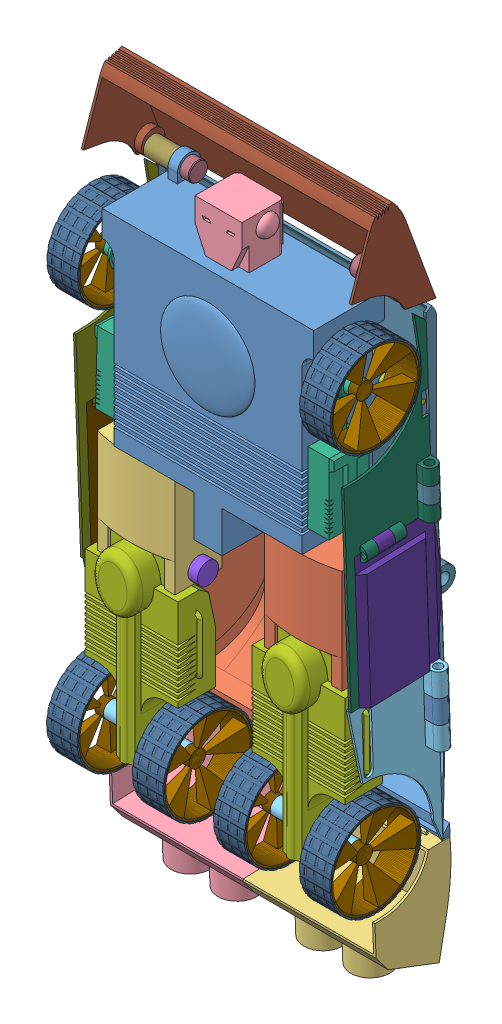
SolidWorks assembly TransformerX_StationaryMode, configuration Default. Lengths in mm.
Overall size (126 297.18 89.36).
45 component instances, 25 part files, 113 mates.
Components (placement in the parent):
- Body-1: Body [Default] at (46.3768 50.8704 65.1566) size (90 111.5 41.19)
- Leg2_left-1: Leg2_left [Default] at (81.8768 16.1704 65.1566) size (33 44.2 22.31)
- Leg2_right-1: Leg2_right [Default] at (10.8768 16.1704 65.1566) size (33 44.2 22.31)
- Head-1: Head [Default] at (46.3768 135.8704 65.1566) size (26 20 18.29)
- Axis-1: Axis [Default] at (81.8768 8.9704 65.1566) x (0 0 1) z (-1 0 0) size (7 7 39)
- Axis-2: Axis [Default] at (10.8768 8.9704 65.1566) x (0 -0.784262 0.62043) z (-1 0 0) size (7 7 39)
- Arm-4: Arm [Default] at (1.8768 74.3852 70.0913) x (-1 0 0) z (0 -0.027558 -0.99962) size (24 60 17)
- Arm-5: Arm [Default] at (90.8768 74.3707 69.1678) x (1 0 0) z (0 0.003878 0.999992) size (24 60 17)
- Leg1-1: Leg1 [Default] at (81.8768 -15.6296 69.1566) size (44.5 80.02 25)
- Leg1-2: Leg1 [Default] at (10.8768 -15.6296 69.1566) size (44.5 80.02 25)
- Axis-3: Axis [Default] at (10.8768 -57.5296 69.1566) x (0 -0.957762 -0.287561) z (-1 0 0) size (7 7 39)
- Axis-4: Axis [Default] at (81.8768 -57.5296 69.1566) x (0 -0.784262 0.62043) z (-1 0 0) size (7 7 39)
- Locker-1: Locker [Default] at (98.3768 8.9704 65.1566) x (0 0.219799 -0.975545) z (1 0 0) size (9 9 4)
- Locker-2: Locker [Default] at (-5.6232 8.9704 65.1566) x (0 0 1) z (-1 0 0) size (9 9 4)
- Locker-3: Locker [Default] at (27.3768 8.9704 65.1566) x (0 0.855004 -0.518621) z (1 0 0) size (9 9 4)
- Locker-4: Locker [Default] at (65.3768 8.9704 65.1566) x (0 -0.128282 -0.991738) z (-1 0 0) size (9 9 4)
- Wheel-1: Wheel [Default] at (-7.3732 -57.5296 69.1566) x (0 0.25642 0.966566) z (-1 0 0) size (37.5 37.5 12.5)
- Wheel-2: Wheel [Default] at (29.1268 -57.5296 69.1566) x (0 -0.360685 0.932688) z (1 0 0) size (37.5 37.5 12.5)
- Wheel-3: Wheel [Default] at (63.6268 -57.5296 69.1566) x (0 0.360685 -0.932688) z (-1 0 0) size (37.5 37.5 12.5)
- Wheel-4: Wheel [Default] at (100.1268 -57.5296 69.1566) x (0 -0.360685 0.932688) z (1 0 0) size (37.5 37.5 12.5)
- Wheel-5: Wheel [Default] at (100.1268 113.3704 69.0166) x (0 0.145658 0.989335) z (1 0 0) size (37.5 37.5 12.5)
- Wheel-6: Wheel [Default] at (-7.3732 113.3704 69.0166) x (0 -0.858748 -0.512398) z (-1 0 0) size (37.5 37.5 12.5)
- Tire-1: Tire [Default] at (63.6268 -57.5296 69.1566) x (0 0.693664 -0.720299) z (1 0 0) size (38.8 38.79 13)
- Tire-2: Tire [Default] at (-7.3732 -57.5296 69.1566) x (0 0.899399 0.437129) z (1 0 0) size (38.8 38.79 13)
- Tire-3: Tire [Default] at (29.1268 -57.5296 69.1566) x (0 -0.851002 0.525162) z (-1 0 0) size (38.8 38.79 13)
- Tire-4: Tire [Default] at (-7.3732 113.3704 69.0166) x (0 -0.247928 -0.968779) z (1 0 0) size (38.8 38.79 13)
- Tire-5: Tire [Default] at (100.1268 -57.5296 69.1566) x (0 -0.693664 0.720299) z (-1 0 0) size (38.8 38.79 13)
- Tire-6: Tire [Default] at (100.1268 113.3704 69.0166) x (0 0.041073 0.999156) z (-1 0 0) size (38.8 38.79 13)
- CarPart1-1: CarPart1 [Default] at (46.3768 146.4917 57.8937) x (0 0.985256 -0.171089) z (-1 0 0) size (40.79 38 115)
- Axis3-1: Axis3 [Default] at (92.1268 139.8704 50.1566) x (0 0 -1) z (1 0 0) size (8 8 19.5)
- Axis3-2: Axis3 [Default] at (0.6268 139.8704 50.1566) x (0 0.924225 0.381849) z (-1 0 0) size (8 8 19.5)
- Locker2-2: Locker2 [Default] at (10.3768 139.8704 50.1566) x (0 0.082275 0.99661) z (-1 0 0) size (8 8 4)
- Locker2-3: Locker2 [Default] at (82.3768 139.8704 50.1566) x (0 -0.889675 -0.456595) z (1 0 0) size (8 8 4)
- CarPart2-1: CarPart2 [Default] at (46.3768 67.0428 42.5993) x (0 0.999342 0.03628) z (-1 0 0) size (131.64 36.94 126)
- CarPart3_left-1: CarPart3_left [Default] at (103.3768 56.1884 72.8454) x (0 0.999342 0.03628) z (-1 0 0) size (132.4 36.62 6.5)
- CarPart3_right-1: CarPart3_right [Default] at (-10.6232 56.1884 72.8454) x (0 0.999342 0.03628) z (-1 0 0) size (132.4 36.62 6.5)
- CarPart_Door_left-1: CarPart_Door_left [Default] at (103.8768 28.4816 57.37) x (0 0.999342 0.03628) z (-1 0 0) size (59.5 53.92 22.75)
- CarPart_Door_right-1: CarPart_Door_right [Default] at (-10.1232 28.4816 57.37) x (0 0.999342 0.03628) z (-1 0 0) size (59.5 53.92 22.75)
- CarPart4_left-1: CarPart4_left [Default] at (74.6268 -33.3547 37.9538) x (0 0.999342 0.03628) z (-1 0 0) size (78.5 35.5 63)
- CarPart4_right-1: CarPart4_right [Default] at (18.1268 -33.3547 37.9538) x (0 0.999342 0.03628) z (-1 0 0) size (78.5 35.5 63)
- CarPart5_left-1: CarPart5_left [Default] at (74.6268 -82.0545 35.6855) x (0 -0.999342 -0.03628) z (1 0 0) size (48.5 32.62 56.5)
- CarPart5_right-1: CarPart5_right [Default] at (18.1268 -82.0545 35.6855) x (0 -0.999342 -0.03628) z (1 0 0) size (48.5 32.62 56.5)
- CarPart6_left-1: CarPart6_left [Default] at (102.8768 -34.287 56.7424) x (0 0.999342 0.03628) z (-1 0 0) size (69 37.62 7.5)
- CarPart6_right-1: CarPart6_right [Default] at (-9.1232 -34.287 56.7424) x (0 0.999342 0.03628) z (-1 0 0) size (69 37.62 7.5)
- Axis4-1: Axis4 [Default] at (46.3768 97.8704 45.1566) x (0 0 1) z (-1 0 0) size (5.5 5.5 113)
Mates (geometry in assembly coordinates):
- Concentric1: concentric aligned: cylinder of Body-1 through (74.3768 40.6704 65.1566) axis (-1 0 0) radius 3.5; cylinder of Leg2_left-1 through (74.3768 40.6704 65.1566) axis (-1 0 0) radius 3.5
- Coincident1: coincident anti-aligned: plane of Body-1 through (74.3768 40.6704 65.1566) normal (1 0 0); plane of Leg2_left-1 through (74.3768 40.6704 65.1566) normal (-1 0 0)
- Concentric2: concentric aligned: cylinder of Body-1 through (18.3768 40.6704 65.1566) axis (1 0 0) radius 3.5; cylinder of Leg2_right-1 through (18.3768 40.6704 65.1566) axis (1 0 0) radius 3.5
- Coincident2: coincident anti-aligned: plane of Body-1 through (18.3768 40.6704 65.1566) normal (-1 0 0); plane of Leg2_right-1 through (18.3768 40.6704 65.1566) normal (1 0 0)
- Parallel1: parallel aligned: plane of Leg2_left-1 through (65.3768 48.1704 55.1566) normal (0 0 -1); plane of Leg2_right-1 through (-5.6232 48.1704 55.1566) normal (0 0 -1)
- Parallel2: parallel aligned: plane of Body-1 through (91.3768 135.8704 50.1566) normal (0 0 -1); plane of Leg2_right-1 through (-5.6232 48.1704 55.1566) normal (0 0 -1)
- Concentric3: concentric aligned: cylinder of Body-1 through (46.3768 142.8704 65.1566) axis (0 -1 0) radius 4.5; cylinder of Head-1 through (46.3768 142.8704 65.1566) axis (0 -1 0) radius 4.5
- Coincident5: coincident anti-aligned: plane of Body-1 through (46.3768 142.8704 65.1566) normal (0 1 0); plane of Head-1 through (46.3768 142.8704 65.1566) normal (0 -1 0)
- Parallel3: parallel aligned: plane of Body-1 through (1.3768 135.8704 80.1566) normal (0 0 1); plane of Head-1 through (46.3768 135.8704 75.6566) normal (0 0 1)
- Concentric4: concentric anti-aligned: cylinder of Leg2_right-1 through (27.3768 8.9704 65.1566) axis (-1 0 0) radius 3.5; cylinder of Axis-2 through (32.2535 8.9704 65.1566) axis (1 0 0) radius 3.5
- Coincident7: coincident aligned: plane of Leg2_right-1 through (27.3768 48.1704 55.1566) normal (1 0 0); plane of Axis-2 through (27.3768 7.0097 66.7076) normal (1 0 0)
- Concentric5: concentric anti-aligned: cylinder of Leg2_left-1 through (98.3768 8.9704 65.1566) axis (-1 0 0) radius 3.5; cylinder of Axis-1 through (103.2535 8.9704 65.1566) axis (1 0 0) radius 3.5
- Coincident8: coincident aligned: plane of Leg2_left-1 through (98.3768 48.1704 55.1566) normal (1 0 0); plane of Axis-1 through (98.3768 8.9704 67.6566) normal (1 0 0)
- Concentric6: concentric aligned: cylinder of Body-1 through (77.3768 113.3704 69.0166) axis (1 0 0) radius 3.5; cylinder of Arm-5 through (77.3768 113.3704 69.0166) axis (1 0 0) radius 3.5
- Coincident9: coincident anti-aligned: plane of Body-1 through (86.3768 50.8704 50.1555) normal (1 0 0); plane of Arm-5 through (86.3768 74.3707 69.1678) normal (-1 0 0)
- Concentric7: concentric aligned: cylinder of Body-1 through (15.3768 113.3704 69.0166) axis (-1 0 0) radius 3.5; cylinder of Arm-4 through (15.3768 113.3704 69.0166) axis (-1 0 0) radius 3.5
- Coincident10: coincident anti-aligned: plane of Body-1 through (6.3768 50.8704 50.1555) normal (-1 0 0); plane of Arm-4 through (6.3768 74.3852 70.0913) normal (1 0 0)
- Concentric8: concentric aligned: cylinder of Axis-1 through (103.2535 8.9704 65.1566) axis (1 0 0) radius 3.5; cylinder of Leg1-1 through (62.1258 8.9704 65.1566) axis (1 0 0) radius 3.75
- Coincident11: coincident anti-aligned: plane of Leg2_left-1 through (93.8768 16.1704 65.1566) normal (-1 0 0); plane of Leg1-1 through (93.8768 8.9704 65.1566) normal (1 0 0)
- Concentric9: concentric anti-aligned: cylinder of Axis-2 through (32.2535 8.9704 65.1566) axis (1 0 0) radius 3.5; cylinder of Leg1-2 through (30.6278 8.9704 65.1566) axis (-1 0 0) radius 3.75
- Coincident12: coincident anti-aligned: plane of Leg2_right-1 through (22.8768 16.1704 65.1566) normal (-1 0 0); plane of Leg1-2 through (22.8768 8.9704 65.1566) normal (1 0 0)
- Parallel4: parallel aligned: plane of Leg1-1 through (67.8768 -45.2296 61.1566) normal (0 0 -1); plane of Leg1-2 through (-3.1232 -45.2296 61.1566) normal (0 0 -1)
- Parallel5: parallel aligned: plane of Leg2_left-1 through (65.3768 48.1704 55.1566) normal (0 0 -1); plane of Leg1-1 through (67.8768 -45.2296 61.1566) normal (0 0 -1)
- Concentric10: concentric anti-aligned: cylinder of Leg1-2 through (30.6278 -57.5296 69.1566) axis (-1 0 0) radius 3.5; cylinder of Axis-3 through (32.2535 -57.5296 69.1566) axis (1 0 0) radius 3.5
- Width2: width aligned: plane of Leg1-2 through (14.8768 -63.0296 77.1566) normal (1 0 0); plane of Leg1-2 through (6.8768 -63.0296 77.1566) normal (-1 0 0); plane of Axis-3 through (27.3768 -59.924 68.4377) normal (1 0 0); plane of Axis-3 through (-5.6232 -60.8818 68.1501) normal (-1 0 0)
- Concentric11: concentric anti-aligned: cylinder of Leg1-1 through (101.6278 -57.5296 69.1566) axis (-1 0 0) radius 3.5; cylinder of Axis-4 through (103.2535 -57.5296 69.1566) axis (1 0 0) radius 3.5
- Width3: width aligned: plane of Leg1-1 through (77.8768 -63.0296 77.1566) normal (-1 0 0); plane of Leg1-1 through (85.8768 -63.0296 77.1566) normal (1 0 0); plane of Axis-4 through (65.3768 -60.2746 71.3281) normal (-1 0 0); plane of Axis-4 through (98.3768 -59.4903 70.7076) normal (1 0 0)
- Concentric12: concentric aligned: cylinder of Axis-2 through (32.2535 8.9704 65.1566) axis (1 0 0) radius 2.5; cylinder of Locker-2 through (-9.6232 8.9704 65.1566) axis (1 0 0) radius 4.5
- Coincident15: coincident anti-aligned: plane of Leg2_right-1 through (-5.6232 48.1704 55.1566) normal (-1 0 0); plane of Locker-2 through (-5.6232 8.9704 65.1566) normal (1 0 0)
- Concentric13: concentric anti-aligned: cylinder of Axis-1 through (103.2535 8.9704 65.1566) axis (1 0 0) radius 2.5; cylinder of Locker-1 through (102.3768 8.9704 65.1566) axis (-1 0 0) radius 4.5
- Coincident16: coincident anti-aligned: plane of Leg2_left-1 through (98.3768 48.1704 55.1566) normal (1 0 0); plane of Locker-1 through (98.3768 8.9704 65.1566) normal (-1 0 0)
- Concentric14: concentric anti-aligned: cylinder of Axis-2 through (32.2535 8.9704 65.1566) axis (1 0 0) radius 2.5; cylinder of Locker-3 through (31.3768 8.9704 65.1566) axis (-1 0 0) radius 4.5
- Coincident17: coincident anti-aligned: plane of Leg2_right-1 through (27.3768 48.1704 55.1566) normal (1 0 0); plane of Locker-3 through (27.3768 8.9704 65.1566) normal (-1 0 0)
- Concentric15: concentric aligned: cylinder of Axis-1 through (103.2535 8.9704 65.1566) axis (1 0 0) radius 2.5; cylinder of Locker-4 through (62.3768 8.9704 65.1566) axis (1 0 0) radius 2.5
- Coincident18: coincident anti-aligned: plane of Leg2_left-1 through (65.3768 48.1704 55.1566) normal (-1 0 0); plane of Locker-4 through (65.3768 8.9704 65.1566) normal (1 0 0)
- Concentric16: concentric aligned: cylinder of Axis-3 through (32.2535 -57.5296 69.1566) axis (1 0 0) radius 2.5; cylinder of Wheel-1 through (-8.6232 -57.5296 69.1566) axis (1 0 0) radius 2.5
- Coincident19: coincident anti-aligned: plane of Axis-3 through (-5.6232 -60.8818 68.1501) normal (-1 0 0); plane of Wheel-1 through (-5.6232 -58.4271 65.7736) normal (1 0 0)
- Concentric17: concentric anti-aligned: cylinder of Axis-3 through (32.2535 -57.5296 69.1566) axis (1 0 0) radius 2.5; cylinder of Wheel-2 through (30.3768 -57.5296 69.1566) axis (-1 0 0) radius 2.5
- Coincident20: coincident anti-aligned: plane of Axis-3 through (27.3768 -59.924 68.4377) normal (1 0 0); plane of Wheel-2 through (27.3768 -56.2672 65.8922) normal (-1 0 0)
- Concentric18: concentric aligned: cylinder of Axis-4 through (103.2535 -57.5296 69.1566) axis (1 0 0) radius 2.5; cylinder of Wheel-3 through (62.3768 -57.5296 69.1566) axis (1 0 0) radius 2.5
- Coincident21: coincident anti-aligned: plane of Axis-4 through (65.3768 -60.2746 71.3281) normal (-1 0 0); plane of Wheel-3 through (65.3768 -58.792 72.421) normal (1 0 0)
- Concentric19: concentric anti-aligned: cylinder of Axis-4 through (103.2535 -57.5296 69.1566) axis (1 0 0) radius 2.5; cylinder of Wheel-4 through (101.3768 -57.5296 69.1566) axis (-1 0 0) radius 2.5
- Coincident22: coincident anti-aligned: plane of Axis-4 through (98.3768 -59.4903 70.7076) normal (1 0 0); plane of Wheel-4 through (98.3768 -56.2672 65.8922) normal (-1 0 0)
- Concentric20: concentric aligned: cylinder of Arm-4 through (-8.6232 113.3704 69.0166) axis (1 0 0) radius 2.5; cylinder of Wheel-6 through (-8.6232 113.3704 69.0166) axis (1 0 0) radius 2.5
- Coincident23: coincident anti-aligned: plane of Arm-4 through (-5.6232 113.3704 69.0166) normal (-1 0 0); plane of Wheel-6 through (-5.6232 116.376 70.81) normal (1 0 0)
- Concentric21: concentric aligned: cylinder of Arm-5 through (101.3768 113.3704 69.0166) axis (-1 0 0) radius 2.5; cylinder of Wheel-5 through (101.3768 113.3704 69.0166) axis (-1 0 0) radius 2.5
- Coincident24: coincident anti-aligned: plane of Arm-5 through (98.3768 113.3704 69.0166) normal (1 0 0); plane of Wheel-5 through (98.3768 112.8606 65.5539) normal (-1 0 0)
- Parallel6: parallel aligned: plane of Wheel-3 through (63.6268 -57.1837 69.6967) normal (0 -0.539304 -0.842111); plane of Wheel-4 through (100.1268 -57.1837 69.6967) normal (0 -0.539304 -0.842111)
- Parallel7: parallel aligned: plane of Wheel-1 through (-7.3732 -57.1837 69.6967) normal (0 -0.539304 -0.842111); plane of Wheel-2 through (29.1268 -57.1837 69.6967) normal (0 -0.539304 -0.842111)
- Parallel8: parallel aligned: plane of Wheel-2 through (29.1268 -57.1837 69.6967) normal (0 -0.539304 -0.842111); plane of Wheel-3 through (63.6268 -57.1837 69.6967) normal (0 -0.539304 -0.842111)
- Concentric22: concentric anti-aligned: cylinder of Wheel-1 through (27.7862 -57.5296 69.1566) axis (1 0 0) radius 18.75; cylinder of Tire-2 through (-0.8722 -57.5296 69.1566) axis (-1 0 0) radius 18.75
- Width4: width aligned: plane of Wheel-1 through (-13.6232 -57.5296 69.1566) normal (-1 0 0); plane of Wheel-1 through (-1.1232 -62.3375 51.0335) normal (1 0 0); plane of Tire-2 through (-13.8732 -57.5296 69.1566) normal (-1 0 0); plane of Tire-2 through (-0.8732 -57.5296 69.1566) normal (1 0 0)
- Concentric23: concentric anti-aligned: cylinder of Wheel-2 through (-6.0326 -57.5296 69.1566) axis (-1 0 0) radius 18.75; cylinder of Tire-3 through (22.6258 -57.5296 69.1566) axis (1 0 0) radius 18.75
- Width5: width aligned: plane of Wheel-2 through (35.3768 -57.5296 69.1566) normal (1 0 0); plane of Wheel-2 through (22.8768 -50.7668 51.6687) normal (-1 0 0); plane of Tire-3 through (35.6268 -57.5296 69.1566) normal (1 0 0); plane of Tire-3 through (22.6268 -57.5296 69.1566) normal (-1 0 0)
- Concentric24: concentric anti-aligned: cylinder of Wheel-3 through (98.7862 -57.5296 69.1566) axis (1 0 0) radius 18.75; cylinder of Tire-1 through (70.1278 -57.5296 69.1566) axis (-1 0 0) radius 18.75
- Width6: width aligned: plane of Wheel-3 through (69.8768 -64.2925 86.6445) normal (1 0 0); plane of Wheel-3 through (57.3768 -57.5296 69.1566) normal (-1 0 0); plane of Tire-1 through (70.1268 -57.5296 69.1566) normal (1 0 0); plane of Tire-1 through (57.1268 -57.5296 69.1566) normal (-1 0 0)
- Concentric25: concentric anti-aligned: cylinder of Wheel-4 through (64.9674 -57.5296 69.1566) axis (-1 0 0) radius 18.75; cylinder of Tire-5 through (93.6258 -57.5296 69.1566) axis (1 0 0) radius 18.75
- Width7: width aligned: plane of Wheel-4 through (93.8768 -50.7668 51.6687) normal (-1 0 0); plane of Wheel-4 through (106.3768 -57.5296 69.1566) normal (1 0 0); plane of Tire-5 through (93.6268 -57.5296 69.1566) normal (-1 0 0); plane of Tire-5 through (106.6268 -57.5296 69.1566) normal (1 0 0)
- Concentric26: concentric anti-aligned: cylinder of Wheel-6 through (27.7862 113.3704 69.0166) axis (1 0 0) radius 18.75; cylinder of Tire-4 through (-0.8722 113.3704 69.0166) axis (-1 0 0) radius 18.75
- Concentric27: concentric anti-aligned: cylinder of Wheel-5 through (64.9674 113.3704 69.0166) axis (-1 0 0) radius 18.75; cylinder of Tire-6 through (93.6258 113.3704 69.0166) axis (1 0 0) radius 18.75
- Width8: width anti-aligned: plane of Wheel-5 through (106.3768 113.3704 69.0166) normal (1 0 0); plane of Wheel-5 through (93.8768 110.6393 50.4665) normal (-1 0 0); plane of Tire-6 through (93.6268 113.3704 69.0166) normal (-1 0 0); plane of Tire-6 through (106.6268 113.3704 69.0166) normal (1 0 0)
- Width9: width aligned: plane of Wheel-6 through (-13.6232 113.3704 69.0166) normal (-1 0 0); plane of Wheel-6 through (-1.1232 129.4719 78.624) normal (1 0 0); plane of Tire-4 through (-13.8732 113.3704 69.0166) normal (-1 0 0); plane of Tire-4 through (-0.8732 113.3704 69.0166) normal (1 0 0)
- Parallel9: parallel aligned: plane of Wheel-4 through (100.1268 -57.1796 69.694) normal (0 -0.545797 -0.837917); plane of Tire-5 through (100.1268 -57.5296 69.1566) normal (0 -0.545797 -0.837917)
- Parallel10: parallel aligned: plane of Wheel-3 through (63.6268 -57.1796 69.694) normal (0 -0.545797 -0.837917); plane of Tire-1 through (63.6268 -57.5296 69.1566) normal (0 -0.545797 -0.837917)
- Parallel11: parallel aligned: plane of Wheel-2 through (29.1268 -57.1796 69.694) normal (0 -0.545797 -0.837917); plane of Tire-3 through (29.1268 -57.5296 69.1566) normal (0 -0.545797 -0.837917)
- Parallel12: parallel aligned: plane of Wheel-1 through (-7.3732 -57.9326 69.6556) normal (0 0.628246 -0.778015); plane of Tire-2 through (-7.3732 -57.5296 69.1566) normal (0 0.628246 -0.778015)
- Parallel13: parallel aligned: plane of Wheel-5 through (100.1268 113.0877 68.4409) normal (0 0.440785 0.897613); plane of Tire-6 through (100.1268 113.3704 69.0166) normal (0 0.440785 0.897613)
- Parallel14: parallel anti-aligned: plane of Wheel-6 through (-7.3732 112.7455 68.8718) normal (0 0.974193 0.225718); plane of Tire-4 through (-7.3732 113.3704 69.0166) normal (0 -0.974193 -0.225718)
- Concentric28: concentric anti-aligned: cylinder of Body-1 through (1.3058 139.8704 50.1566) axis (1 0 0) radius 2.5; cylinder of CarPart1-1 through (101.8768 139.8704 50.1566) axis (-1 0 0) radius 2.5
- Width10: width anti-aligned: plane of Body-1 through (91.3768 135.8704 80.1566) normal (1 0 0); plane of Body-1 through (1.3768 135.8704 50.1566) normal (-1 0 0); plane of CarPart1-1 through (-11.1232 128.6596 72.1015) normal (-1 0 0); plane of CarPart1-1 through (103.8768 128.6596 72.1015) normal (1 0 0)
- Concentric30: concentric aligned: cylinder of CarPart1-1 through (101.8768 139.8704 50.1566) axis (-1 0 0) radius 2.5; cylinder of Axis3-1 through (63.5942 139.8704 50.1566) axis (-1 0 0) radius 2.5
- Coincident36: coincident anti-aligned: plane of Body-1 through (88.3768 139.8704 50.1566) normal (1 0 0); plane of Axis3-1 through (88.3768 139.8704 47.6566) normal (-1 0 0)
- Concentric31: concentric anti-aligned: cylinder of Body-1 through (15.4479 139.8704 50.1566) axis (-1 0 0) radius 2.5; cylinder of Axis3-2 through (29.1595 139.8704 50.1566) axis (1 0 0) radius 2.5
- Coincident37: coincident anti-aligned: plane of CarPart1-1 through (-7.1232 141.0527 49.9513) normal (1 0 0); plane of Axis3-2 through (-7.1232 143.5673 51.684) normal (-1 0 0)
- Concentric32: concentric anti-aligned: cylinder of Axis3-2 through (29.1595 139.8704 50.1566) axis (1 0 0) radius 2.5; cylinder of Locker2-2 through (10.3768 139.8704 50.1566) axis (-1 0 0) radius 2.5
- Coincident38: coincident anti-aligned: plane of Body-1 through (8.3768 139.8704 50.1566) normal (1 0 0); plane of Locker2-2 through (8.3768 139.8704 50.1566) normal (-1 0 0)
- Concentric34: concentric aligned: cylinder of Locker2-3 through (-59.0523 139.8704 50.1566) axis (-1 0 0) radius 4; cylinder of Axis3-1 through (63.5942 139.8704 50.1566) axis (-1 0 0) radius 2.5
- Coincident39: coincident anti-aligned: plane of Body-1 through (84.3768 139.8704 50.1566) normal (-1 0 0); plane of Locker2-3 through (84.3768 139.8704 50.1566) normal (1 0 0)
- Parallel15: parallel aligned: plane of Body-1 through (91.3768 135.8704 50.1566) normal (0 0 -1); plane of CarPart2-1 through (174.8356 124.7511 -21.0898) normal (0 0 -1)
- Width12: width anti-aligned: plane of Body-1 through (86.3768 50.8704 50.1555) normal (1 0 0); plane of Body-1 through (6.3768 50.8704 50.1555) normal (-1 0 0); plane of CarPart2-1 through (-11.1232 130.581 -18.5169) normal (-1 0 0); plane of CarPart2-1 through (103.8768 67.1154 40.6006) normal (1 0 0)
- Concentric36: concentric aligned: cylinder of CarPart2-1 through (106.3768 73.1371 -15.599) axis (0 -0.999342 -0.03628) radius 1.75; cylinder of CarPart3_left-1 through (106.3768 79.8827 -15.3541) axis (0 -0.999342 -0.03628) radius 1.75
- Coincident42: coincident anti-aligned: plane of CarPart2-1 through (106.3768 68.1906 -15.7786) normal (0 0.999342 0.03628); plane of CarPart3_left-1 through (106.3768 68.1906 -15.7786) normal (0 -0.999342 -0.03628)
- Concentric37: concentric aligned: cylinder of CarPart2-1 through (-13.6232 73.1371 -15.599) axis (0 -0.999342 -0.03628) radius 1.75; cylinder of CarPart3_right-1 through (-13.6232 79.8827 -15.3541) axis (0 -0.999342 -0.03628) radius 1.75
- Coincident43: coincident anti-aligned: plane of CarPart2-1 through (-13.6232 61.1952 -16.0326) normal (0 -0.999342 -0.03628); plane of CarPart3_right-1 through (-13.6232 61.1952 -16.0326) normal (0 0.999342 0.03628)
- Parallel16: parallel aligned: plane of Body-1 through (6.3768 50.8704 50.1555) normal (-1 0 0); plane of CarPart3_right-1 through (-11.1232 108.9987 13.3411) normal (-1 0 0)
- Parallel17: parallel aligned: plane of Body-1 through (86.3768 50.8704 50.1555) normal (1 0 0); plane of CarPart3_left-1 through (103.8768 108.9987 13.3411) normal (1 0 0)
- Concentric38: concentric aligned: cylinder of CarPart3_right-1 through (-12.5232 53.2299 17.3204) axis (0 0.03628 -0.999342) radius 1.25; cylinder of CarPart_Door_right-1 through (-12.5232 53.5008 9.8609) axis (0 0.03628 -0.999342) radius 1.25
- Coincident46: coincident anti-aligned: plane of CarPart3_right-1 through (-11.1232 53.883 -0.6677) normal (0 -0.03628 0.999342); plane of CarPart_Door_right-1 through (-11.1232 53.883 -0.6677) normal (0 0.03628 -0.999342)
- Concentric39: concentric anti-aligned: cylinder of CarPart3_left-1 through (105.2768 54.1927 -9.1977) axis (0 -0.03628 0.999342) radius 1.25; cylinder of CarPart_Door_left-1 through (105.2768 53.5008 9.8609) axis (0 0.03628 -0.999342) radius 1.25
- Coincident47: coincident anti-aligned: plane of CarPart3_left-1 through (103.8768 53.883 -0.6677) normal (0 -0.03628 0.999342); plane of CarPart_Door_left-1 through (102.8768 53.883 -0.6677) normal (0 0.03628 -0.999342)
- Parallel18: parallel aligned: plane of CarPart3_left-1 through (103.8768 108.9987 13.3411) normal (1 0 0); plane of CarPart_Door_left-1 through (106.3768 47.8589 -13.895) normal (1 0 0)
- Parallel19: parallel aligned: plane of CarPart3_right-1 through (-11.1232 108.9987 13.3411) normal (-1 0 0); plane of CarPart_Door_right-1 through (-13.6232 47.8589 -13.895) normal (-1 0 0)
- Concentric40: concentric aligned: cylinder of CarPart2-1 through (14.3058 4.0176 -46.6271) axis (1 0 0) radius 2.5; cylinder of CarPart4_left-1 through (54.3058 4.0176 -46.6271) axis (1 0 0) radius 2.5
- Coincident50: coincident anti-aligned: plane of CarPart2-1 through (61.3768 4.0176 -46.6271) normal (1 0 0); plane of CarPart4_left-1 through (61.3768 4.0176 -46.6271) normal (-1 0 0)
- Concentric41: concentric aligned: cylinder of CarPart2-1 through (28.4479 4.0176 -46.6271) axis (-1 0 0) radius 2.5; cylinder of CarPart4_right-1 through (38.4479 4.0176 -46.6271) axis (-1 0 0) radius 2.5
- Coincident51: coincident anti-aligned: plane of CarPart2-1 through (31.3768 4.0176 -46.6271) normal (-1 0 0); plane of CarPart4_right-1 through (31.3768 4.0176 -46.6271) normal (1 0 0)
- Parallel20: parallel aligned: plane of CarPart2-1 through (46.3768 -101.1843 -46.944) normal (0 0.03628 -0.999342); plane of CarPart4_left-1 through (-19.9606 -1.1061 -43.3108) normal (0 0.03628 -0.999342)
- Coincident53: coincident aligned: plane of CarPart2-1 through (46.3768 -101.1843 -46.944) normal (0 0.03628 -0.999342); plane of CarPart4_right-1 through (-76.4606 -1.1061 -43.3108) normal (0 0.03628 -0.999342)
- Concentric42: concentric anti-aligned: cylinder of CarPart4_right-1 through (6.6168 -69.8595 -23.7923) axis (-1 0 0) radius 0.35; cylinder of CarPart5_right-1 through (-0.3631 -69.8595 -23.7923) axis (1 0 0) radius 0.35
- Coincident55: coincident anti-aligned: plane of CarPart4_right-1 through (0.6268 -69.8595 -23.7923) normal (-1 0 0); plane of CarPart5_right-1 through (0.6268 -69.8595 -23.7923) normal (1 0 0)
- Concentric43: concentric anti-aligned: cylinder of CarPart4_left-1 through (61.1369 -69.8595 -23.7923) axis (1 0 0) radius 0.35; cylinder of CarPart5_left-1 through (58.1168 -69.8595 -23.7923) axis (-1 0 0) radius 0.35
- Coincident56: coincident anti-aligned: plane of CarPart4_left-1 through (92.1268 -69.8595 -23.7923) normal (1 0 0); plane of CarPart5_left-1 through (92.1268 -69.8595 -23.7923) normal (-1 0 0)
- Parallel21: parallel anti-aligned: plane of CarPart4_left-1 through (74.6268 -70.2141 -27.8078) normal (0 -0.999342 -0.03628); plane of CarPart5_left-1 through (46.3768 -71.8928 4.6526) normal (0 0.999342 0.03628)
- Parallel22: parallel aligned: plane of CarPart5_left-1 through (136.8768 -85.3865 -28.9156) normal (0 -0.188517 -0.98207); plane of CarPart5_right-1 through (80.3768 -85.3865 -28.9156) normal (0 -0.188517 -0.98207)
- Concentric45: concentric anti-aligned: cylinder of CarPart4_right-1 through (-13.6232 -7.0238 -19.5098) axis (0 -0.999342 -0.03628) radius 1.75; cylinder of CarPart6_right-1 through (-13.6232 -36.9036 -20.5946) axis (0 0.999342 0.03628) radius 1.75
- Coincident59: coincident anti-aligned: plane of CarPart4_right-1 through (-13.6232 -21.9637 -20.0522) normal (0 -0.999342 -0.03628); plane of CarPart6_right-1 through (-13.6232 -21.9637 -20.0522) normal (0 0.999342 0.03628)
- Concentric46: concentric aligned: cylinder of CarPart4_left-1 through (106.3768 -26.9102 -20.2318) axis (0 0.999342 0.03628) radius 1.75; cylinder of CarPart6_left-1 through (106.3768 -36.9036 -20.5946) axis (0 0.999342 0.03628) radius 1.75
- Coincident60: coincident anti-aligned: plane of CarPart4_left-1 through (106.3768 -21.9637 -20.0522) normal (0 -0.999342 -0.03628); plane of CarPart6_left-1 through (106.3768 -21.9637 -20.0522) normal (0 0.999342 0.03628)
- Parallel23: parallel aligned: plane of CarPart_Door_right-1 through (-13.6232 47.8589 -13.895) normal (-1 0 0); plane of CarPart6_right-1 through (-10.1232 -62.633 9.0805) normal (-1 0 0)
- Parallel24: parallel aligned: plane of CarPart_Door_left-1 through (106.3768 47.8589 -13.895) normal (1 0 0); plane of CarPart6_left-1 through (102.8768 -62.633 9.0805) normal (1 0 0)
- Concentric47: concentric anti-aligned: cylinder of Body-1 through (93.4479 97.8704 45.1566) axis (-1 0 0) radius 2.5; cylinder of Axis4-1 through (117.7908 97.8704 45.1566) axis (1 0 0) radius 2.5
- Coincident61: coincident aligned: plane of CarPart2-1 through (102.8768 95.1296 -16.3645) normal (1 0 0); plane of Axis4-1 through (102.8768 97.8704 46.1716) normal (1 0 0)
- Concentric48: concentric anti-aligned: cone of CarPart2-1 through (-7.1232 97.8704 45.1566) axis (-1 0 0); cylinder of Axis4-1 through (117.7908 97.8704 45.1566) axis (1 0 0) radius 2.5
